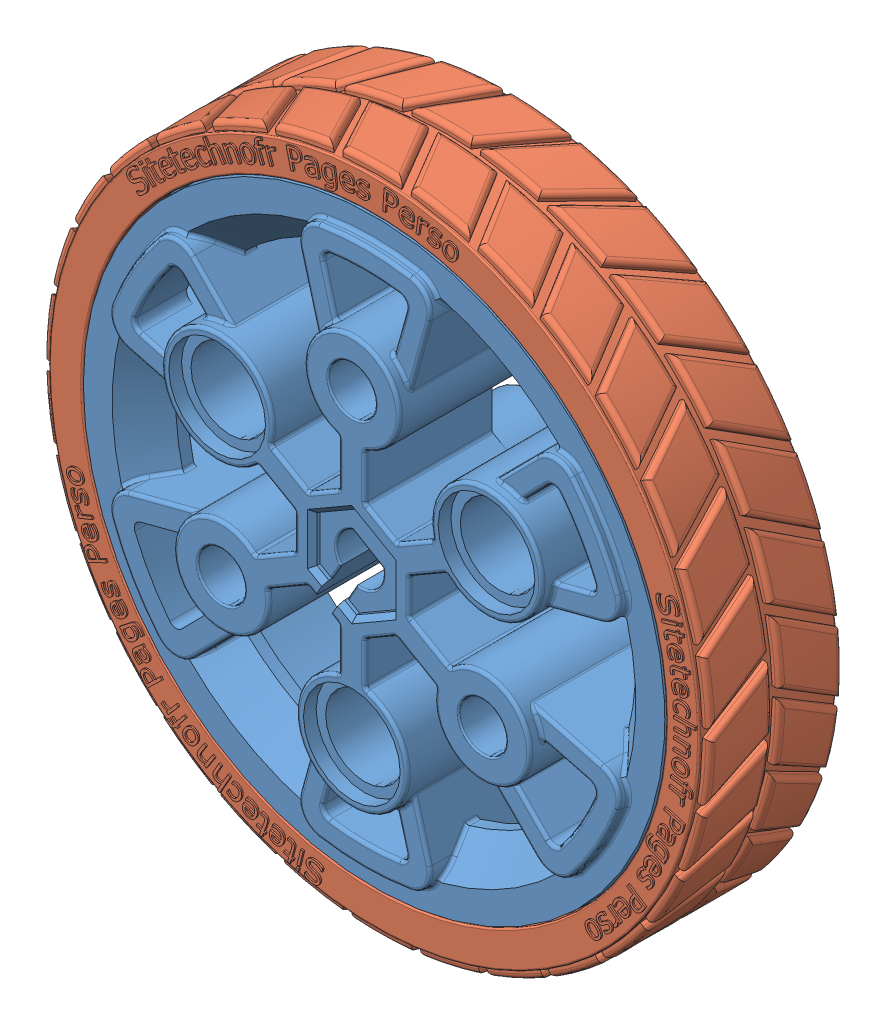
SolidWorks assembly Assemblage Roue, configuration Défaut. Lengths in mm.
Overall size (42.1 42.08 11.71).
2 component instances, 2 part files, 3 mates.
Components (placement in the parent):
- Jante-1: Jante [Défaut] at (-4.5177 1.0603 38.5548) size (38.8 38.8 11.71)
- Pneu-1: Pneu [Défaut] at (-4.5177 1.0603 43.2548) x (0 0 -1) z (1 0 0) size (8.8 42.08 42.1)
Mates (geometry in assembly coordinates):
- Coaxiale1: concentric anti-aligned: cylinder of Jante-1 through (-4.5177 1.0603 42.4548) axis (0 0 -1) radius 19.4; cylinder of Pneu-1 through (-4.5177 1.0603 43.2548) axis (0 0 1) radius 21
- Coïncidente1: coincident aligned: plane of Jante-1 through (-4.5177 1.0603 34.5548) normal (0 0 -1); plane of Pneu-1 through (-4.5177 22.0603 34.5548) normal (0 0 -1)
- Parallèle1: parallel anti-aligned: plane of Jante-1 through (-4.5177 3.4103 38.5548) normal (0 -1 0); plane of Pneu-1 through (14.3899 3.3103 38.3548) normal (0 1 0)
